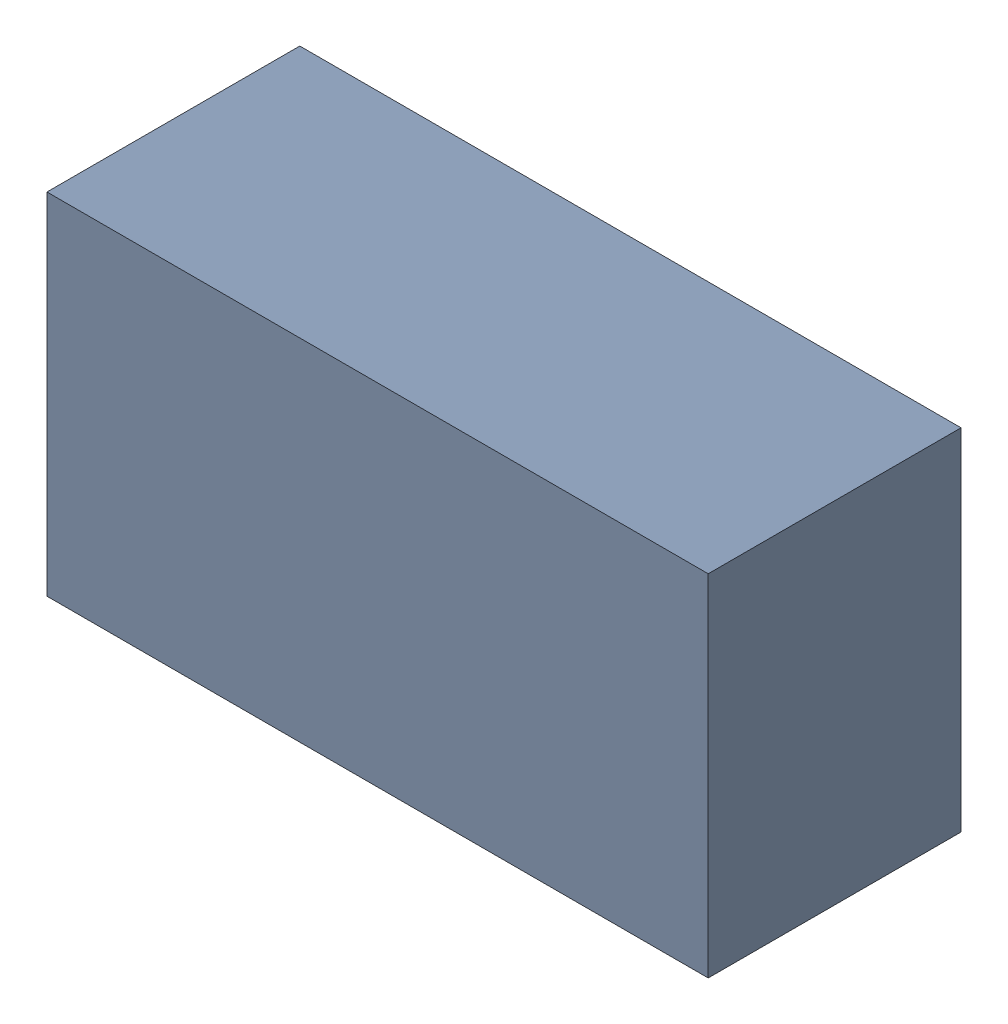
SolidWorks assembly C17, configuration Default. Lengths in mm.
Overall size (3.4 1.8 1.3).
2 component instances, 1 part files, 0 mates.
Components (placement in the parent):
- 1017092976-1: 1017092976 [Default] at (37.465 90.805 0) size (3.4 1.8 1.3)
  - Extruded_4-1: Extruded_4 [Default] at origin size (3.4 1.8 1.3)
